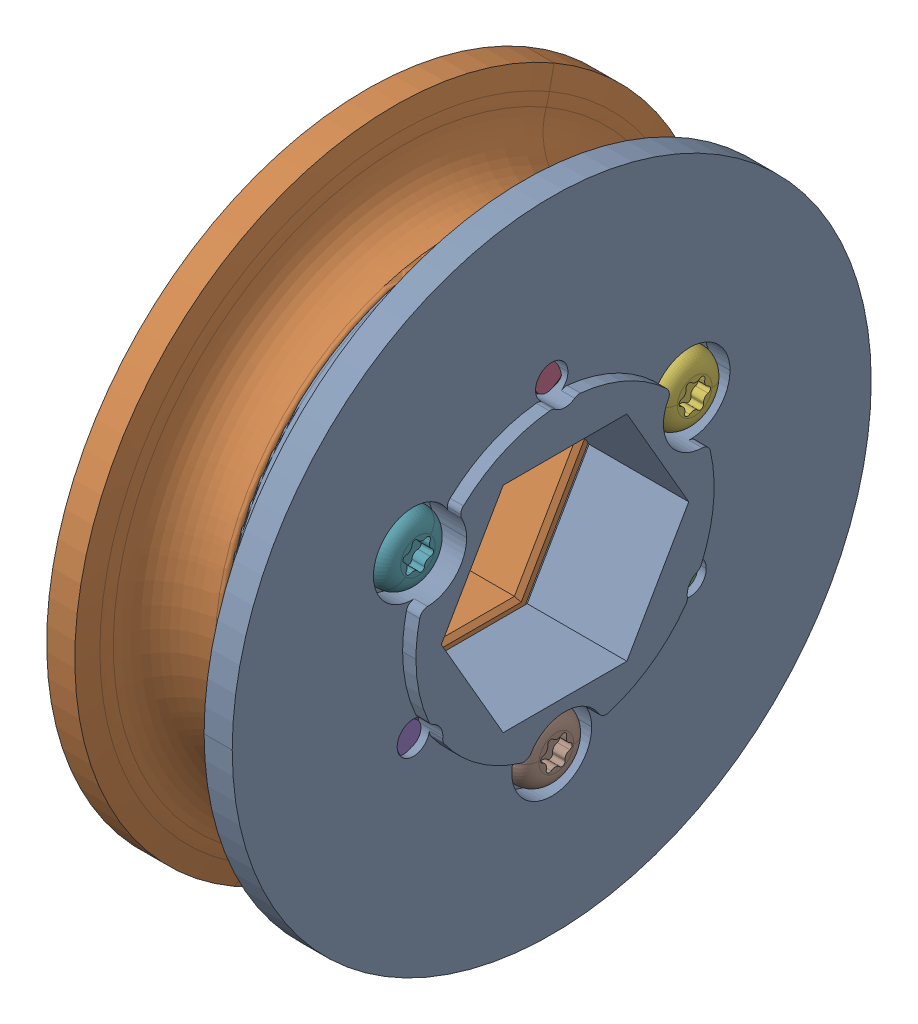
SolidWorks assembly WCP-0096 Rev6-4.step, configuration Default. Lengths in mm.
Overall size (12.65 52.05 52.05).
8 component instances, 2 part files, 0 mates.
Components (placement in the parent):
- WCP-0096-001 Rev6.step-1: WCP-0096-001 Rev6.step [Default] at origin size (7.57 38.1 38.1)
- WCP-0096-001 Rev6.step-2: WCP-0096-001 Rev6.step [Default] x (-1 0 0) z (0 0.866025 -0.5) size (7.57 38.1 38.1)
- WCP-0356 Rev1.step-1: WCP-0356 Rev1.step [Default] at (0.4817 -4.7625 -8.2489) x (0 -0.126969 0.991907) z (0 -0.991907 -0.126969) size (4.06 11.05 4.06)
- WCP-0356 Rev1.step-2: WCP-0356 Rev1.step [Default] at (0.4817 9.525 0) x (0 0.866766 0.498715) z (0 -0.498715 0.866766) size (4.06 11.05 4.06)
- WCP-0356 Rev1.step-3: WCP-0356 Rev1.step [Default] at (0.4817 -4.7625 8.2489) x (0 -0.994015 -0.109248) z (0 0.109248 -0.994015) size (4.06 11.05 4.06)
- WCP-0356 Rev1.step-4: WCP-0356 Rev1.step [Default] at (-0.4817 4.7625 -8.2489) x (0 -0.997555 0.069879) z (0 0.069879 0.997555) size (4.06 11.05 4.06)
- WCP-0356 Rev1.step-5: WCP-0356 Rev1.step [Default] at (-0.4817 4.7625 8.2489) x (0 -0.7202 -0.693767) z (0 -0.693767 0.7202) size (4.06 11.05 4.06)
- WCP-0356 Rev1.step-6: WCP-0356 Rev1.step [Default] at (-0.4817 -9.525 0) x (0 -0.997555 0.069879) z (0 0.069879 0.997555) size (4.06 11.05 4.06)
